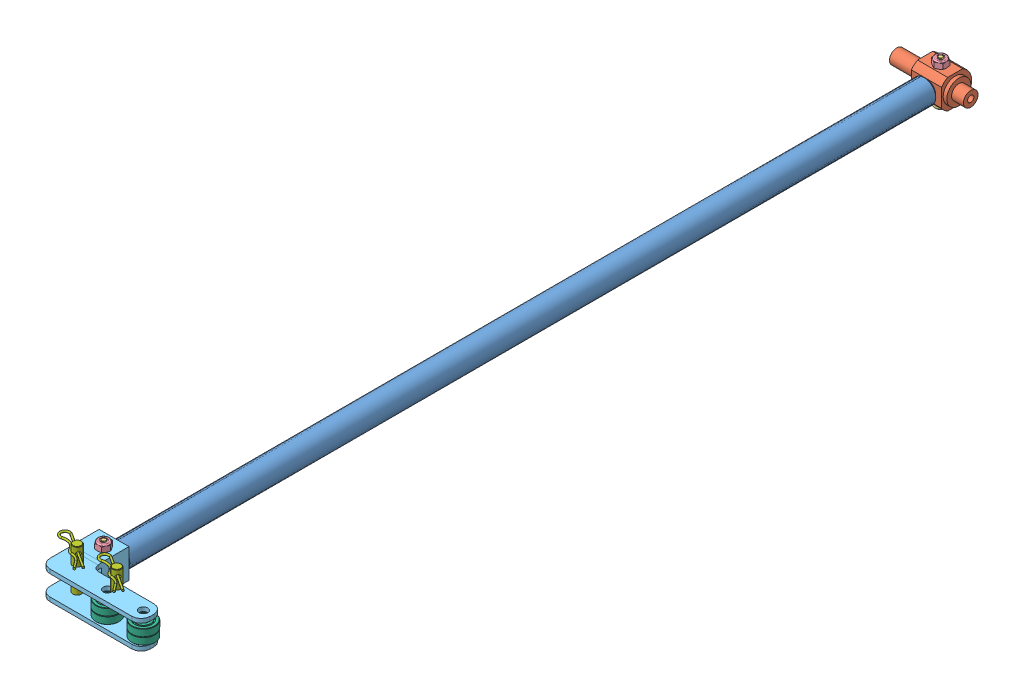
SolidWorks assembly LAS-01-0000, configuration Default. Lengths in mm.
Overall size (71.67 28.69 493.13).
14 component instances, 8 part files, 27 mates.
Components (placement in the parent):
- LAS-01-0004-1: LAS-01-0004 [Default] at (0 0 9) x (0 -1 0) z (0 0 1) size (12.7 12.7 474.2)
- LAS-01-0002-1: LAS-01-0002 [Default] x (-1 0 0) z (0 0 1) size (40.5 16 16.5)
- LAS-01-0006-1: LAS-01-0006 [Default] at (20 0 450.7) x (0 1 0) z (0 0 1) size (16 38 15) (hidden)
- 97345A104_316 STAINLESS STEEL SHOULDER SCREW-1: 97345A104_316 STAINLESS STEEL SHOULDER SCREW [97345A104] at (0 -11.175 0) x (0.837169 0 0.546944) z (0 -1 0) size (6.35 6.35 23.39)
- 90715A005_TYPE 316 STAINLESS STEEL NYLON-INSERT LOCKNUT-1: 90715A005_TYPE 316 STAINLESS STEEL NYLON-INSERT LOCKNUT [90715A005] at (0 8 0) size (6.35 3.66 7.33)
- 90715A005_TYPE 316 STAINLESS STEEL NYLON-INSERT LOCKNUT-2: 90715A005_TYPE 316 STAINLESS STEEL NYLON-INSERT LOCKNUT [90715A005] at (0 8 458.2) x (-0.837169 0 0.546944) z (-0.546944 0 -0.837169) size (6.35 3.66 7.33)
- 97345A104_316 STAINLESS STEEL SHOULDER SCREW-2: 97345A104_316 STAINLESS STEEL SHOULDER SCREW [97345A104] at (0 -11.175 458.2) x (-1 0 0) z (0 -1 0) size (6.35 6.35 23.39)
- LAS-01-0008-1: LAS-01-0008 [Default] at (0 0 450.7) x (0 1 0) z (0 0 1) size (16 55 32)
- 5908K620_ULTRA-CORROSION-RESISTANT SS BALL BEARING-1: 5908K620_ULTRA-CORROSION-RESISTANT SS BALL BEARING [5908K62] at (20.5653 -2.5156 476.7) x (1 0 0) z (0 -1 0) size (12.7 12.7 3.97)
- 5908K620_ULTRA-CORROSION-RESISTANT SS BALL BEARING-2: 5908K620_ULTRA-CORROSION-RESISTANT SS BALL BEARING [5908K62] at (20.5653 1.4531 476.7) x (1 0 0) z (0 -1 0) size (12.7 12.7 3.97)
- 5908K620_ULTRA-CORROSION-RESISTANT SS BALL BEARING-3: 5908K620_ULTRA-CORROSION-RESISTANT SS BALL BEARING [5908K62] at (40.2375 -2.5156 476.7) x (-0.176244 0 -0.984346) z (0 -1 0) size (12.7 12.7 3.97)
- 5908K620_ULTRA-CORROSION-RESISTANT SS BALL BEARING-4: 5908K620_ULTRA-CORROSION-RESISTANT SS BALL BEARING [5908K62] at (40.2375 1.4531 476.7) x (0.982082 0 -0.188455) z (0 -1 0) size (12.7 12.7 3.97)
- 92401A576_316 STAINLESS STEEL CLEVIS PIN-1: 92401A576_316 STAINLESS STEEL CLEVIS PIN [92401A576] at (0 4.7 472.7) x (0.837169 0 0.546944) z (0 -1 0) size (26.11 9.36 27.18)
- 92401A576_316 STAINLESS STEEL CLEVIS PIN-2: 92401A576_316 STAINLESS STEEL CLEVIS PIN [92401A576] at (21.7 4.7 472.7) x (0.837169 0 0.546944) z (0 -1 0) size (26.11 9.36 27.18)
Mates (geometry in assembly coordinates):
- Coincident16: coincident aligned: plane of PIVOT ARM-1 through (0 0 0) normal (0 0 1)
- Coincident18: coincident anti-aligned: plane of PIVOT ARM-1 through (0 0 0) normal (-1 0 0)
- Slot1: slot anti-aligned: cylinder of LAS-01-0004-1 through (0.508 4.7625 0) axis (0 1 0) radius 1.5875; cylinder of LAS-01-0002-1 through (0 -8 0) axis (0 -1 0) radius 1.5875; cylinder of LAS-01-0004-1 through (-0.508 4.7625 0) axis (0 1 0) radius 1.5875
- Concentric3: concentric aligned: cylinder of LAS-01-0004-1 through (0 0 -8) axis (0 0 1) radius 4.7625; cylinder of PIVOT ARM-1 through (0 0 7.5) axis (0 0 1) radius 4.7625
- Concentric4: concentric anti-aligned: cylinder of LAS-01-0002-1 through (0 -8 0) axis (0 -1 0) radius 1.5875; cylinder of 90265A143_18-8 STAINLESS STEEL SHOULDER SCREW-1 through (0 18 0) axis (0 1 0) radius 3
- Coincident19: coincident anti-aligned: plane of LAS-01-0002-1 through (0 -8 0) normal (0 -1 0); plane of 90265A143_18-8 STAINLESS STEEL SHOULDER SCREW-1 through (0 -8 -5) normal (0 1 0)
- ProfileCenter1: profile center = 0 mm aligned: circle of 97345A165_316 STAINLESS STEEL SHOULDER SCREW-1; circle of PIVOT ARM-1
- ProfileCenter2: profile center = 0 mm aligned: circle of 90101A225_TYPE 18-8 SS THIN NYLON-INSERT LOCKNUT-1; circle of PIVOT ARM-1
- Concentric5: concentric aligned: cylinder of LAS-01-0004-1 through (0 0 450.2) axis (0 0 1) radius 4.7625; cylinder of LAS-01-0006-1 through (0 0 465.7) axis (0 0 1) radius 4.7625
- Coincident21: coincident anti-aligned: plane of PIVOT ARM-1 through (0 0 0) normal (0 -1 0)
- ProfileCenter3: profile center = 0 mm anti-aligned: circle of 97345A165_316 STAINLESS STEEL SHOULDER SCREW-2; circle of tetherGuide-1
- ProfileCenter4: profile center = 0 mm aligned: circle of 90101A225_TYPE 18-8 SS THIN NYLON-INSERT LOCKNUT-2; circle of tetherGuide-1
- ProfileCenter7: profile center = 0 mm aligned: circle of PIVOT ARM-1; circle of 90205A313_TYPE 316 STAINLESS STEEL NARROW HEX NUT-4
- Slot2: slot aligned: cylinder of ? through (0 -15.8125 458.2) axis (0 -1 0) radius 3.175; cylinder of LAS-01-0004-1 through (0.508 -4.7625 458.2) axis (0 -1 0) radius 1.5875; cylinder of LAS-01-0004-1 through (-0.25 -4.7625 458.2) axis (0 -1 0) radius 3.175
- ProfileCenter9: profile center = 0 mm aligned: circle of 97345A104_316 STAINLESS STEEL SHOULDER SCREW-1; circle of LAS-01-0002-1
- ProfileCenter10: profile center = 0 mm aligned: plane of 90715A005_TYPE 316 STAINLESS STEEL NYLON-INSERT LOCKNUT-1 through (-3.175 8 -5.4993) normal (0 -1 0); circle of LAS-01-0002-1
- ProfileCenter11: profile center = 0 mm anti-aligned: circle of LAS-01-0006-1; circle of 97345A104_316 STAINLESS STEEL SHOULDER SCREW-2
- ProfileCenter12: profile center = 0 mm aligned: circle of LAS-01-0006-1; plane of 90715A005_TYPE 316 STAINLESS STEEL NYLON-INSERT LOCKNUT-2 through (5.6658 8 461.0673) normal (0 -1 0)
- Slot3: slot anti-aligned: cylinder of 97345A104_316 STAINLESS STEEL SHOULDER SCREW-2 through (0 11.8438 458.2) axis (0 1 0) radius 1.5875; cylinder of LAS-01-0004-1 through (-0.508 -4.7625 458.2) axis (0 -1 0) radius 1.5875; cylinder of LAS-01-0004-1 through (0.508 -4.7625 458.2) axis (0 -1 0) radius 1.5875
- Concentric7: concentric aligned: cylinder of LAS-01-0004-1 through (0 0 450.2) axis (0 0 1) radius 4.7625; cylinder of LAS-01-0008-1 through (0 0 482.7) axis (0 0 1) radius 4.7625
- Concentric8: concentric anti-aligned: cylinder of 97345A104_316 STAINLESS STEEL SHOULDER SCREW-2 through (0 11.8438 458.2) axis (0 1 0) radius 1.5875; cylinder of LAS-01-0008-1 through (0 -8 458.2) axis (0 -1 0) radius 1.5875
- ProfileCenter13: profile center = 1 mm aligned: circle of 5908K620_ULTRA-CORROSION-RESISTANT SS BALL BEARING-1; circle of LAS-01-0008-1
- ProfileCenter14: profile center = 0 mm aligned: circle of 5908K620_ULTRA-CORROSION-RESISTANT SS BALL BEARING-2; circle of 5908K620_ULTRA-CORROSION-RESISTANT SS BALL BEARING-1
- ProfileCenter15: profile center = 0 mm aligned: circle of 5908K620_ULTRA-CORROSION-RESISTANT SS BALL BEARING-4; circle of 5908K620_ULTRA-CORROSION-RESISTANT SS BALL BEARING-3
- ProfileCenter16: profile center = 1 mm aligned: circle of 5908K620_ULTRA-CORROSION-RESISTANT SS BALL BEARING-3; circle of LAS-01-0008-1
- ProfileCenter18: profile center = 0 mm: circle of 92401A576_316 STAINLESS STEEL CLEVIS PIN-1; circle of LAS-01-0008-1
- ProfileCenter19: profile center = 0 mm: circle of 92401A576_316 STAINLESS STEEL CLEVIS PIN-2; circle of LAS-01-0008-1
